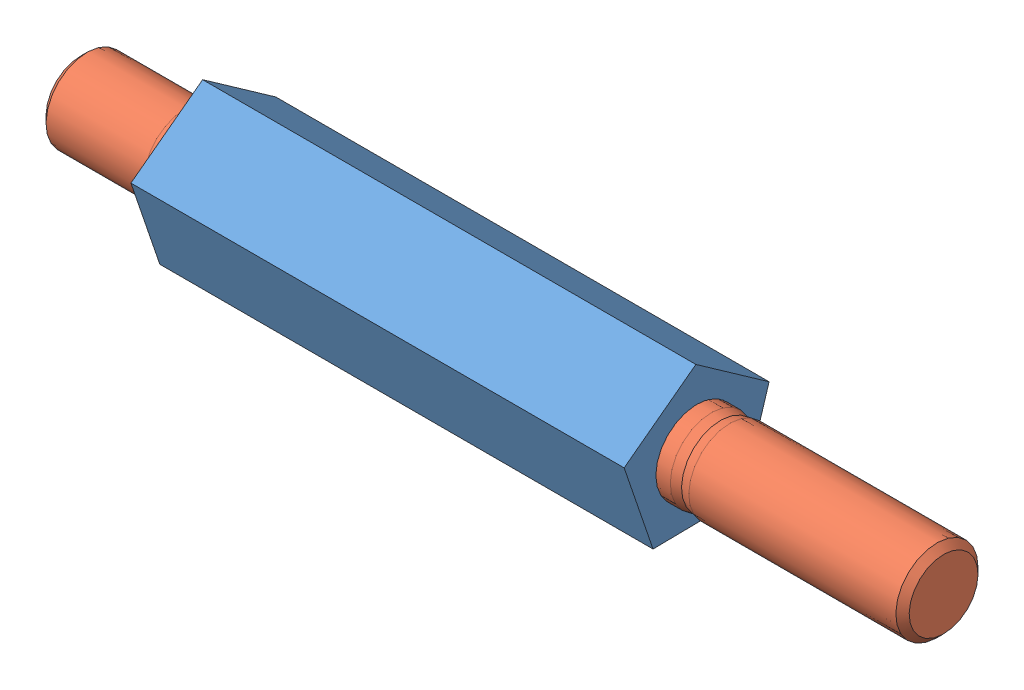
SolidWorks assembly Assem_rod, configuration Default. Lengths in mm.
Overall size (105 16.85 17.63).
2 component instances, 2 part files, 2 mates.
Components (placement in the parent):
- steering_rod_2-1: steering_rod_2 [Default] at (-14.8087 -2.3348 8.9078) size (60 16.85 17.63)
- double end studs bm=1.5d_am-5: double end studs bm=1.5d_am [AM A M10X90-C] at (-59.8087 -2.3348 8.9078) x (1 0 0) z (0 0.97127 0.23798) size (105 10 10)
Mates (geometry in assembly coordinates):
- Concentric5: concentric aligned: cylinder of steering_rod_2-1 through (15.1913 -2.3348 8.9078) axis (-1 0 0) radius 5; cylinder of double end studs bm=1.5d_am-5 through (-61.1196 -2.3348 8.9078) axis (-1 0 0) radius 5
- Coincident4: coincident anti-aligned: circle of steering_rod_2-1; circle of double end studs bm=1.5d_am-5
